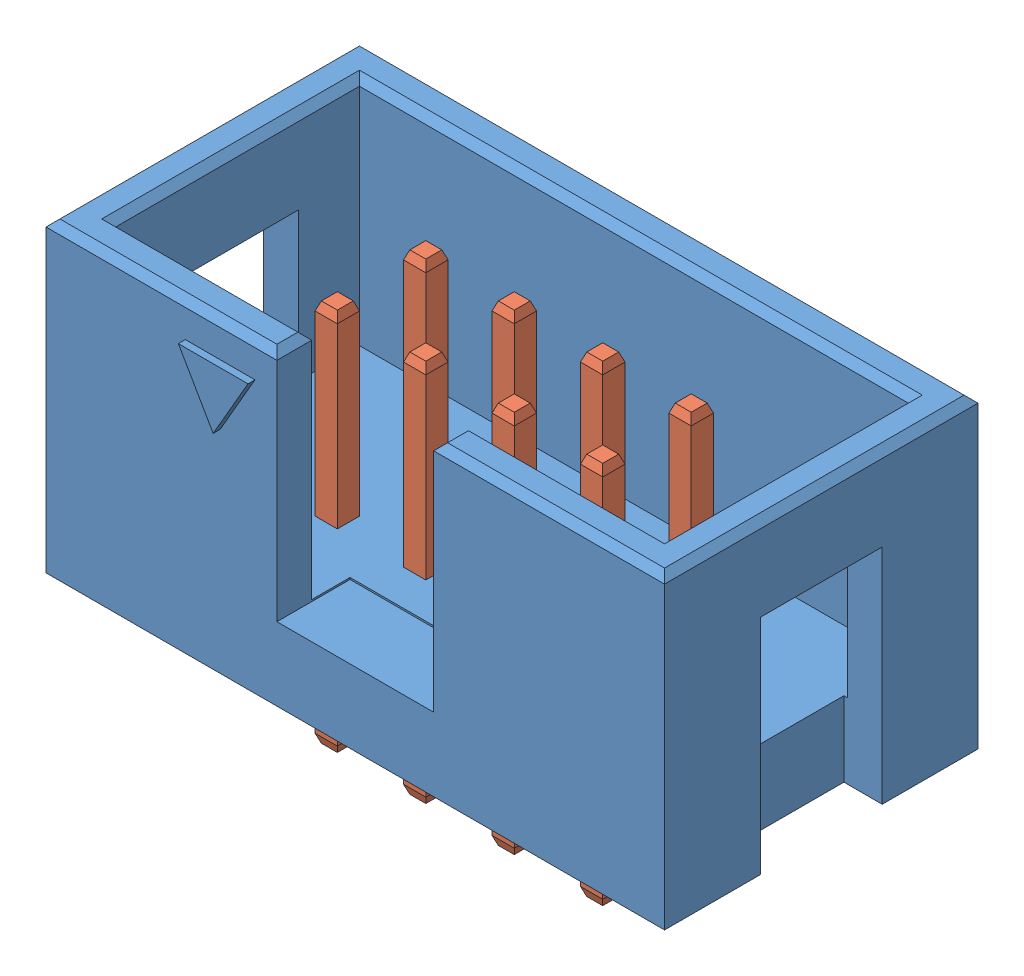
SolidWorks assembly conector IDC2_54-2x4p, configuration Default. Lengths in mm.
Overall size (17.76 12.3 9.2).
9 component instances, 2 part files, 0 mates.
Components (placement in the parent):
- conector IDC2_54-2x4p_carcasa-1: conector IDC2_54-2x4p_carcasa [Default] at origin size (17.76 9 9.2)
- pin 0_64x11-1: pin 0_64x11 [Default] at (-12.84 -3.5 -5.985) size (0.64 11 0.64)
- pin 0_64x11-2: pin 0_64x11 [Default] at (-12.84 -3.5 -3.445) size (0.64 11 0.64)
- pin 0_64x11-3: pin 0_64x11 [Default] at (-10.3 -3.5 -5.985) size (0.64 11 0.64)
- pin 0_64x11-4: pin 0_64x11 [Default] at (-10.3 -3.5 -3.445) size (0.64 11 0.64)
- pin 0_64x11-5: pin 0_64x11 [Default] at (-7.76 -3.5 -5.985) size (0.64 11 0.64)
- pin 0_64x11-6: pin 0_64x11 [Default] at (-7.76 -3.5 -3.445) size (0.64 11 0.64)
- pin 0_64x11-7: pin 0_64x11 [Default] at (-5.22 -3.5 -5.985) size (0.64 11 0.64)
- pin 0_64x11-8: pin 0_64x11 [Default] at (-5.22 -3.5 -3.445) size (0.64 11 0.64)
